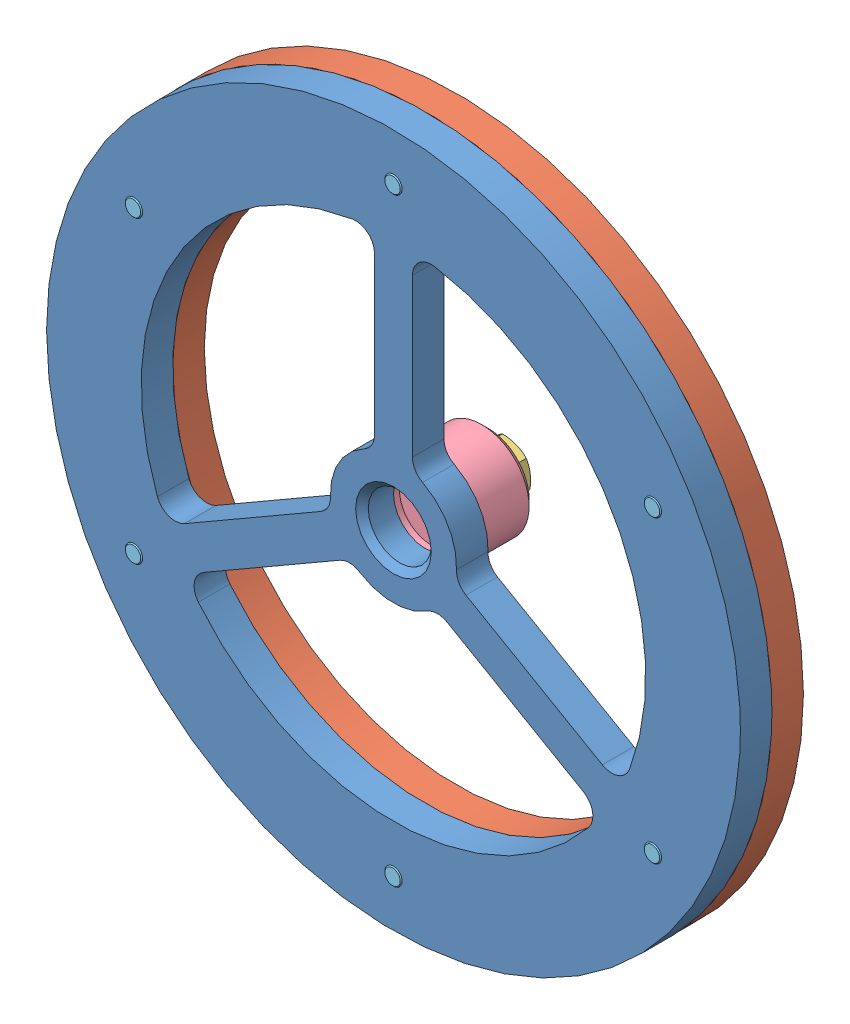
SolidWorks assembly Flywheel, configuration Défaut. Lengths in mm.
Overall size (110 110 18.35).
10 component instances, 5 part files, 10 mates.
Components (placement in the parent):
- Flywheel_1-1: Flywheel_1 [Défaut] at (-6.5376 -0.2514 107.5) size (110 110 5)
- Flywheel_2-1: Flywheel_2 [Défaut] at (-6.5376 -0.2514 107.5) x (-1 0 0) z (0 0 -1) size (110 110 5)
- ecrou_nfeniso_4032_m4_10-1: ecrou_nfeniso_4032_m4_10 [Default] at (-6.5376 -0.2514 94.3) x (-0.783756 -0.621069 0) z (0 0 1) size (8.08 7 3.2)
- Nut-1: Nut [Défaut] at (-6.5376 -0.2514 107.5) x (-1 0 0) z (0 0 -1) size (15 15 10)
- din_en_24017_m3x10-1: din_en_24017_m3x10 [Default] at (-47.6738 -24.0014 102.65) size (5.5 6.35 12)
- din_en_24017_m3x10-2: din_en_24017_m3x10 [Default] at (-47.6738 23.4986 102.65) x (0.5 -0.866025 0) z (0 0 1) size (5.5 6.35 12)
- din_en_24017_m3x10-3: din_en_24017_m3x10 [Default] at (-6.5376 47.2486 102.65) x (-0.5 -0.866025 0) z (0 0 1) size (5.5 6.35 12)
- din_en_24017_m3x10-4: din_en_24017_m3x10 [Default] at (34.5986 23.4986 102.65) x (-1 0 0) z (0 0 1) size (5.5 6.35 12)
- din_en_24017_m3x10-5: din_en_24017_m3x10 [Default] at (34.5986 -24.0014 102.65) x (-0.5 0.866025 0) z (0 0 1) size (5.5 6.35 12)
- din_en_24017_m3x10-6: din_en_24017_m3x10 [Default] at (-6.5376 -47.7514 102.65) x (0.5 0.866025 0) z (0 0 1) size (5.5 6.35 12)
Mates (geometry in assembly coordinates):
- Coïncidente4: coincident anti-aligned: plane of Flywheel_1-1 through (-6.5376 -0.2514 107.5) normal (0 0 -1); plane of Flywheel_2-1 through (-6.5376 -0.2514 107.5) normal (0 0 1)
- Coaxiale2: concentric anti-aligned: circle of Flywheel_1-1; circle of Flywheel_2-1
- Coaxiale3: concentric anti-aligned: circle of Flywheel_1-1; circle of Flywheel_2-1
- Coaxiale4: concentric aligned: circle of Flywheel_2-1; circle of ?
- Coaxiale5: concentric anti-aligned: circle of Flywheel_1-1; circle of ecrou_nfeniso_4032_m4_10-1
- Coaxiale6: concentric anti-aligned: circle of Flywheel_1-1; circle of Nut-1
- Coïncidente5: coincident anti-aligned: plane of Flywheel_1-1 through (-6.5376 -0.2514 107.5) normal (0 0 -1); plane of Nut-1 through (-6.5376 -0.2514 107.5) normal (0 0 1)
- Coïncidente6: coincident anti-aligned: plane of ecrou_nfeniso_4032_m4_10-1 through (-9.2808 -2.4252 97.5) normal (0 0 1); plane of Nut-1 through (-6.5376 -0.2514 97.5) normal (0 0 -1)
- Coïncidente8: coincident anti-aligned: plane of Flywheel_2-1 through (-6.5376 -0.2514 102.5) normal (0 0 -1); plane of din_en_24017_m3x10-1 through (-47.6738 -24.0014 102.5) normal (0 0 1)
- Coaxiale8: concentric aligned: circle of Flywheel_2-1; circle of din_en_24017_m3x10-1
